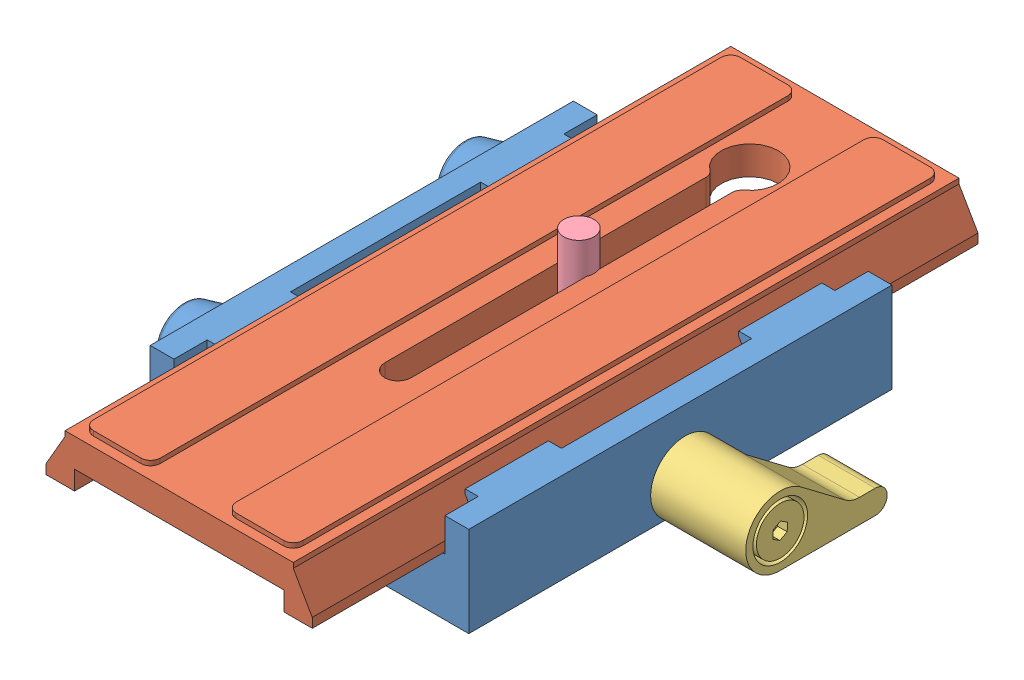
SolidWorks assembly manfrotto_357, configuration По умолчанию. Lengths in mm.
Overall size (96 28.95 140).
4 component instances, 4 part files, 5 mates.
Components (placement in the parent):
- female-1: female [По умолчанию] at (3.0358 -0.1566 -43.8793) size (76 19 89)
- male-1: male [По умолчанию] at (3.1132 2.3434 -67.3946) size (56 11 140)
- screw-1: screw [По умолчанию] at (37.5358 -2.6566 0.6207) x (0 0 -1) z (1 0 0) size (29.75 14.5 20)
- round head bolt_ai-1: round head bolt_ai [RHBOLT 0.25-20x0.5x0.5-N] at (2.9446 2.9144 -11.6251) x (0 1 0) z (-0.138315 0 -0.990388) size (16.13 14.71 14.71)
Mates (geometry in assembly coordinates):
- Совпадение1: coincident anti-aligned: plane of female-1 through (37.5358 -2.6566 0.6207) normal (1 0 0); plane of screw-1 through (37.5358 -2.6566 0.6207) normal (-1 0 0)
- Концентричный1: concentric aligned: circle of female-1; circle of screw-1
- Совпадение3: coincident anti-aligned: plane of female-1 through (-25.4642 2.3434 -43.8793) normal (0 1 0); plane of male-1 through (-24.8868 2.3434 72.6054) normal (0 -1 0)
- Совпадение4: coincident anti-aligned: plane of female-1 through (-25.4642 3.3434 -43.8793) normal (0.866025 -0.5 0); plane of male-1 through (-20.8868 11.2716 72.6054) normal (-0.866025 0.5 0)
- Совпадение5: coincident anti-aligned: plane of male-1 through (3.1132 6.3434 -67.3946) normal (0 -1 0); plane of round head bolt_ai-1 through (10.2273 6.3434 -12.6422) normal (0 1 0)
